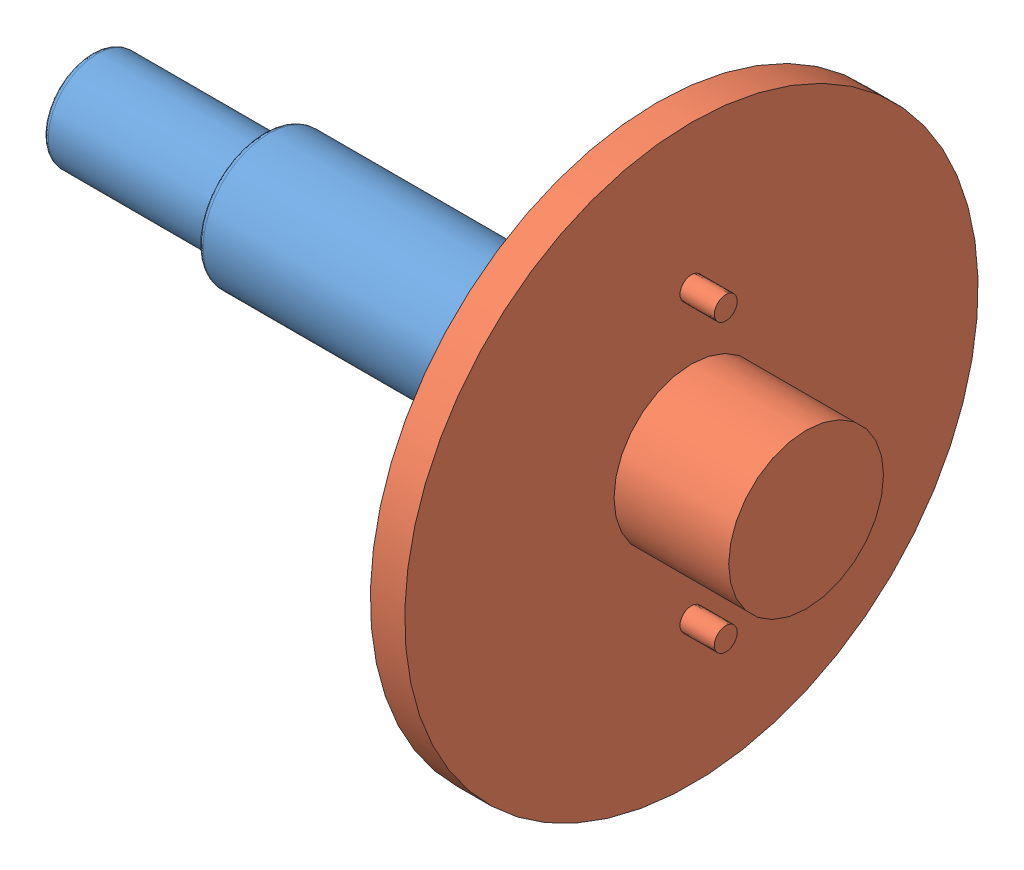
SolidWorks assembly Assemblage1, configuration Défaut. Lengths in mm.
Overall size (124.65 100 100).
2 component instances, 2 part files, 3 mates.
Components (placement in the parent):
- Axe Tour-1: Axe Tour [Défaut] at (12.7674 10.6499 120) size (120 23 23)
- Appui plan centrage 3D-1: Appui plan centrage 3D [Défaut] at (-1.3142 10.6499 134.1186) x (0 0 1) z (0 1 0) size (100 26 100)
Mates (geometry in assembly coordinates):
- Coaxiale1: concentric: cylinder of Axe Tour-1 through (12.7674 10.6499 120) axis (1 0 0) radius 8.5; cylinder of Appui plan centrage 3D-1 through (83.003 10.6499 120) axis (1 0 0) radius 13.5
- Coïncidente9: coincident: plane of Axe Tour-1 through (-12.2326 20.0549 126.5) normal (0 0 1); plane of Appui plan centrage 3D-1 through (16.4146 10.6499 126.5) normal (0 0 -1)
- Coïncidente10: coincident anti-aligned: plane of Axe Tour-1 through (12.7674 19.1499 120) normal (1 0 0); plane of Appui plan centrage 3D-1 through (12.7674 10.6499 120) normal (-1 0 0)
